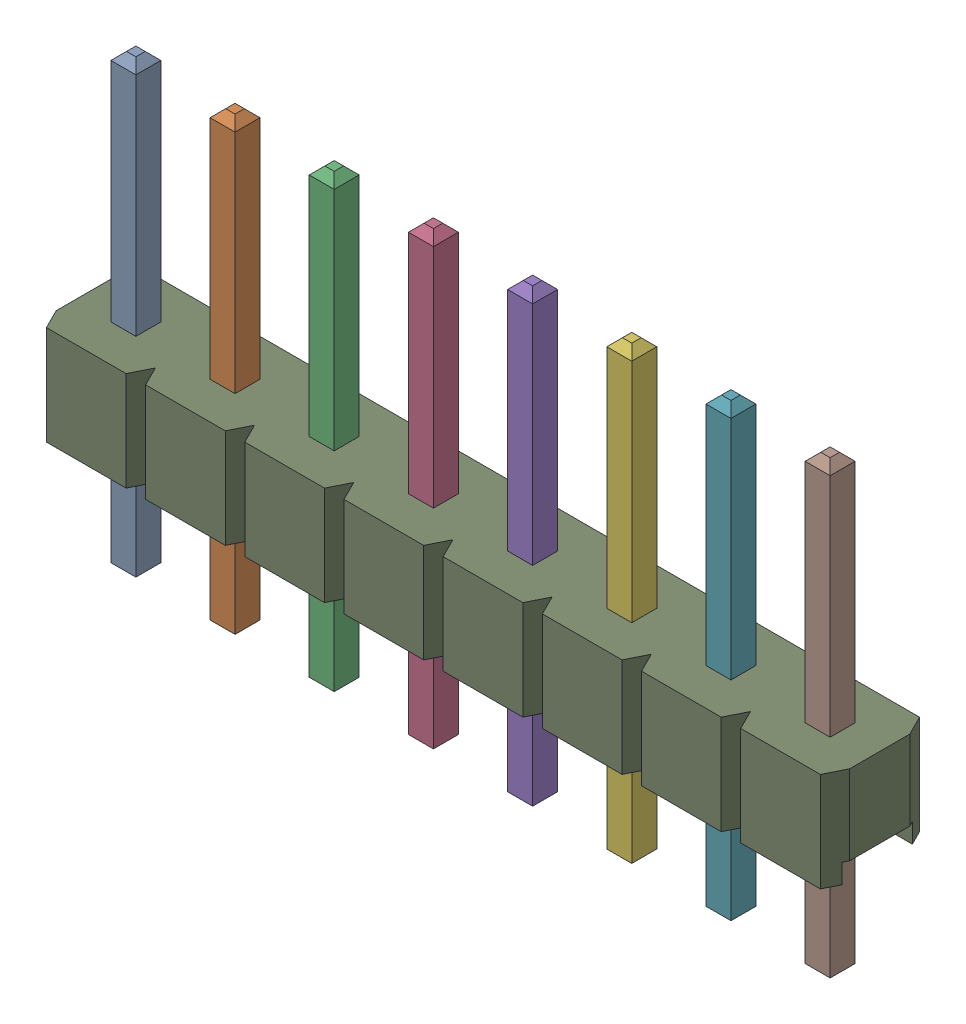
SolidWorks assembly 61300811121, configuration Default. Lengths in mm.
Overall size (20.32 11.54 2.54).
9 component instances, 2 part files, 0 mates.
Components (placement in the parent):
- 6130xx11121_PIN_2-1: 6130xx11121_PIN_2 [Default] at (-8.89 1.5 0) x (1 0 0) z (0 -1 0) size (0.64 0.64 11.54)
- 6130xx11121_PIN_2-2: 6130xx11121_PIN_2 [Default] at (-6.35 1.5 0) x (1 0 0) z (0 -1 0) size (0.64 0.64 11.54)
- 6130xx11121_PIN_2-3: 6130xx11121_PIN_2 [Default] at (-3.81 1.5 0) x (1 0 0) z (0 -1 0) size (0.64 0.64 11.54)
- 6130xx11121_PIN_2-4: 6130xx11121_PIN_2 [Default] at (-1.27 1.5 0) x (1 0 0) z (0 -1 0) size (0.64 0.64 11.54)
- 6130xx11121_PIN_2-5: 6130xx11121_PIN_2 [Default] at (1.27 1.5 0) x (1 0 0) z (0 -1 0) size (0.64 0.64 11.54)
- 6130xx11121_PIN_2-6: 6130xx11121_PIN_2 [Default] at (3.81 1.5 0) x (1 0 0) z (0 -1 0) size (0.64 0.64 11.54)
- 6130xx11121_PIN_2-7: 6130xx11121_PIN_2 [Default] at (6.35 1.5 0) x (1 0 0) z (0 -1 0) size (0.64 0.64 11.54)
- 6130xx11121_PIN_2-8: 6130xx11121_PIN_2 [Default] at (8.89 1.5 0) x (1 0 0) z (0 -1 0) size (0.64 0.64 11.54)
- 61300811121-1: 61300811121 [Default] at origin size (20.32 2.54 2.54)
